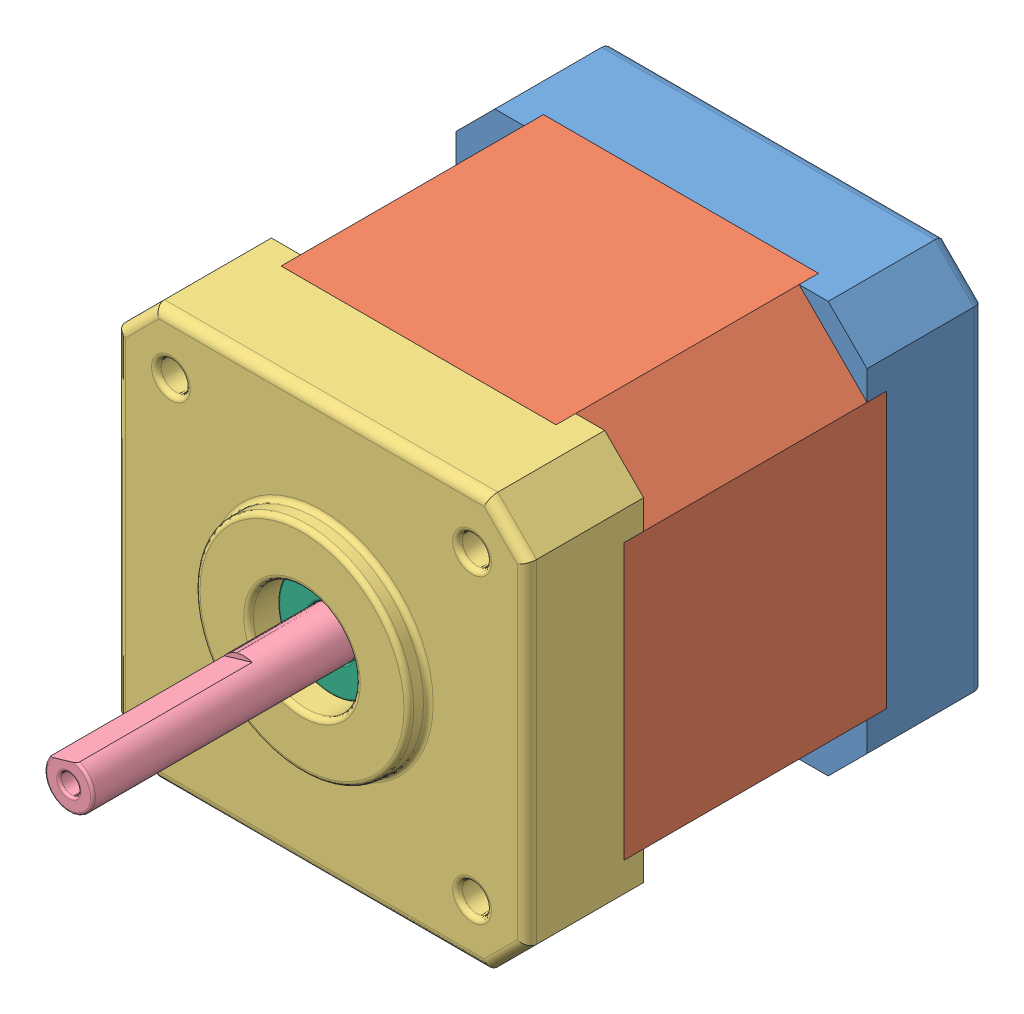
SolidWorks assembly 40MM_NEMA17, configuration Predeterminado. Lengths in mm.
Overall size (42.3 42.3 73.04).
10 component instances, 6 part files, 31 mates.
Components (placement in the parent):
- Base-1: Base [Predeterminado] at (-10.3955 4.6172 0) size (42.3 42.3 12)
- Body1-1: Body1 [Predeterminado] at (-10.3955 4.6172 10) size (42.3 42.3 27)
- FaceCap-1: FaceCap [Predeterminado] at (-10.3955 4.6172 47) x (-1 0 0) z (0 0 -1) size (42.3 42.3 14)
- Shaft1-1: Shaft1 [Predeterminado] at (-10.3955 4.6172 0) x (0.958742 0.284277 0) z (0 0 1) size (5 5 73.04)
- 92005A126_METRIC PAN HEAD PHILLIPS MACHINE SCREW-4: 92005A126_METRIC PAN HEAD PHILLIPS MACHINE SCREW [92005A126] at (5.1045 20.1172 19) x (-1 0 0) z (0 0 -1) size (6 6 18.5)
- 92005A126_METRIC PAN HEAD PHILLIPS MACHINE SCREW-5: 92005A126_METRIC PAN HEAD PHILLIPS MACHINE SCREW [92005A126] at (-25.8955 20.1172 19) x (-1 0 0) z (0 0 -1) size (6 6 18.5)
- 92005A126_METRIC PAN HEAD PHILLIPS MACHINE SCREW-6: 92005A126_METRIC PAN HEAD PHILLIPS MACHINE SCREW [92005A126] at (5.1045 -10.8828 19) x (-1 0 0) z (0 0 -1) size (6 6 18.5)
- 92005A126_METRIC PAN HEAD PHILLIPS MACHINE SCREW-7: 92005A126_METRIC PAN HEAD PHILLIPS MACHINE SCREW [92005A126] at (-25.8955 -10.8828 19) x (-1 0 0) z (0 0 -1) size (6 6 18.5)
- Bearing3-1: Bearing3 [Default] at (-10.3955 4.6172 1) x (0.989862 0.142029 0) z (0 0 1) size (11 11 4)
- Bearing3-2: Bearing3 [Default] at (-10.3955 4.6172 42) x (0.862541 0.505988 0) z (0 0 1) size (11 11 4)
Mates (geometry in assembly coordinates):
- Paralelo1: parallel anti-aligned: plane of Base-1 through (-10.3955 4.6172 10) normal (0 0 1); plane of Body1-1 through (-10.3955 4.6172 10) normal (0 0 -1)
- Coincidente2: coincident aligned: plane of Base-1 through (-27.5455 25.7672 12) normal (0 1 0); plane of Body1-1 through (-24.5455 25.7672 37) normal (0 1 0)
- Coincidente3: coincident aligned: plane of Base-1 through (-31.5455 21.7672 12) normal (-1 0 0); plane of Body1-1 through (-31.5455 18.7672 37) normal (-1 0 0)
- Coincidente4: coincident anti-aligned: plane of Base-1 through (-10.3955 4.6172 10) normal (0 0 1); plane of Body1-1 through (-10.3955 4.6172 10) normal (0 0 -1)
- Coincidente5: coincident anti-aligned: plane of Body1-1 through (-10.3955 4.6172 37) normal (0 0 1); plane of FaceCap-1 through (-10.3955 4.6172 37) normal (0 0 -1)
- Coincidente6: coincident aligned: plane of Body1-1 through (-31.5455 18.7672 37) normal (-1 0 0); plane of FaceCap-1 through (-31.5455 21.7672 35) normal (-1 0 0)
- Coincidente7: coincident aligned: plane of Body1-1 through (-24.5455 25.7672 37) normal (0 1 0); plane of FaceCap-1 through (6.7545 25.7672 35) normal (0 1 0)
- Concéntrica5: concentric aligned: cylinder of Base-1 through (5.1045 20.1172 22) axis (0 0 -1) radius 1.5; cylinder of ? through (5.1045 20.1172 -24.8) axis (0 0 -1) radius 1.5
- Coincidente8: coincident anti-aligned: plane of Base-1 through (5.1045 20.1172 3) normal (0 0 -1); plane of ? through (5.7706 21.4612 3) normal (0 0 1)
- Concéntrica10: concentric aligned: cylinder of Base-1 through (-10.3955 4.6172 22) axis (0 0 -1) radius 2.5; cylinder of Shaft1-1 through (-10.3955 4.6172 73) axis (0 0 -1) radius 2.5
- Concéntrica14: concentric aligned: cylinder of Shaft1-1 through (-10.3955 4.6172 73) axis (0 0 -1) radius 2.5; cylinder of ? through (-10.3955 4.6172 64.225) axis (0 0 -1) radius 3.175
- Concéntrica15: concentric anti-aligned: cylinder of Shaft1-1 through (-10.3955 4.6172 73) axis (0 0 -1) radius 2.5; cylinder of ? through (-10.3955 4.6172 -17.225) axis (0 0 1) radius 6.35
- Coincidente12: coincident aligned: plane of Base-1 through (-10.3955 4.6172 0) normal (0 0 -1); plane of Shaft1-1 through (-10.3955 4.6172 0) normal (0 0 -1)
- Coincident1: coincident anti-aligned: plane of FaceCap-1 through (-10.3955 4.6172 42) normal (0 0 1); plane of ? through (-9.6923 7.8434 42) normal (0 0 -1)
- Coincident2: coincident anti-aligned: plane of Base-1 through (-10.3955 4.6172 5) normal (0 0 -1); plane of ? through (-13.3263 6.1382 5) normal (0 0 1)
- Concentric1: concentric anti-aligned: cylinder of Base-1 through (5.1045 20.1172 22) axis (0 0 -1) radius 1.5; cylinder of 92005A126_METRIC PAN HEAD PHILLIPS MACHINE SCREW-4 through (5.1045 20.1172 19) axis (0 0 1) radius 3
- Coincident3: coincident anti-aligned: plane of Base-1 through (5.1045 20.1172 3) normal (0 0 -1); plane of 92005A126_METRIC PAN HEAD PHILLIPS MACHINE SCREW-4 through (5.1045 20.1172 3) normal (0 0 1)
- Parallel1: parallel aligned: plane of Base-1 through (-27.5455 25.7672 12) normal (0 1 0); plane of 92005A126_METRIC PAN HEAD PHILLIPS MACHINE SCREW-4 through (5.1045 20.1172 19) normal (0 1 0)
- Coincident5: coincident anti-aligned: plane of Base-1 through (5.1045 20.1172 3) normal (0 0 -1); plane of 92005A126_METRIC PAN HEAD PHILLIPS MACHINE SCREW-5 through (-25.8955 20.1172 3) normal (0 0 1)
- Parallel2: parallel aligned: plane of Base-1 through (-27.5455 25.7672 12) normal (0 1 0); plane of 92005A126_METRIC PAN HEAD PHILLIPS MACHINE SCREW-5 through (-25.8955 20.1172 19) normal (0 1 0)
- Concentric2: concentric anti-aligned: cylinder of Base-1 through (-25.8955 20.1172 22) axis (0 0 -1) radius 1.5; cylinder of 92005A126_METRIC PAN HEAD PHILLIPS MACHINE SCREW-5 through (-25.8955 20.1172 19) axis (0 0 1) radius 3
- Coincident6: coincident anti-aligned: plane of Base-1 through (5.1045 20.1172 3) normal (0 0 -1); plane of 92005A126_METRIC PAN HEAD PHILLIPS MACHINE SCREW-6 through (5.1045 -10.8828 3) normal (0 0 1)
- Parallel3: parallel aligned: plane of Base-1 through (-27.5455 25.7672 12) normal (0 1 0); plane of 92005A126_METRIC PAN HEAD PHILLIPS MACHINE SCREW-6 through (5.1045 -10.8828 19) normal (0 1 0)
- Concentric3: concentric anti-aligned: cylinder of Base-1 through (5.1045 -10.8828 22) axis (0 0 -1) radius 1.5; cylinder of 92005A126_METRIC PAN HEAD PHILLIPS MACHINE SCREW-6 through (5.1045 -10.8828 19) axis (0 0 1) radius 3
- Coincident7: coincident anti-aligned: plane of Base-1 through (5.1045 20.1172 3) normal (0 0 -1); plane of 92005A126_METRIC PAN HEAD PHILLIPS MACHINE SCREW-7 through (-25.8955 -10.8828 3) normal (0 0 1)
- Parallel4: parallel aligned: plane of Base-1 through (-27.5455 25.7672 12) normal (0 1 0); plane of 92005A126_METRIC PAN HEAD PHILLIPS MACHINE SCREW-7 through (-25.8955 -10.8828 19) normal (0 1 0)
- Concentric4: concentric anti-aligned: cylinder of Base-1 through (-25.8955 -10.8828 22) axis (0 0 -1) radius 1.5; cylinder of 92005A126_METRIC PAN HEAD PHILLIPS MACHINE SCREW-7 through (-25.8955 -10.8828 19) axis (0 0 1) radius 3
- Concentric5: concentric aligned: cylinder of Shaft1-1 through (-10.3955 4.6172 73) axis (0 0 -1) radius 2.5; cylinder of Bearing3-1 through (-10.3955 4.6172 5) axis (0 0 -1) radius 2.5
- Coincident9: coincident anti-aligned: plane of Base-1 through (-10.3955 4.6172 5) normal (0 0 -1); plane of Bearing3-1 through (-10.3955 4.6172 5) normal (0 0 1)
- Concentric6: concentric aligned: cylinder of Shaft1-1 through (-10.3955 4.6172 73) axis (0 0 -1) radius 2.5; cylinder of Bearing3-2 through (-10.3955 4.6172 46) axis (0 0 -1) radius 2.5
- Coincident10: coincident anti-aligned: plane of FaceCap-1 through (-10.3955 4.6172 42) normal (0 0 1); plane of Bearing3-2 through (-10.3955 4.6172 42) normal (0 0 -1)
